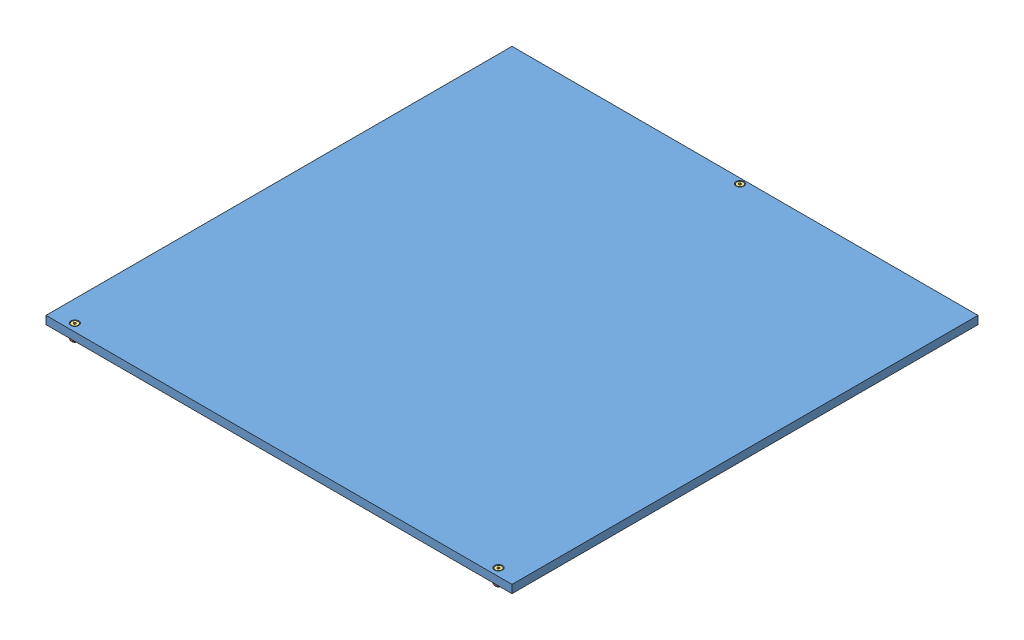
SolidWorks assembly Assem1, configuration Default. Lengths in mm.
Overall size (550 18.52 550.07).
7 component instances, 3 part files, 9 mates.
Components (placement in the parent):
- 550x550_plate-1: 550x550_plate [Default] at origin size (550 9.53 550)
- m4_threaded_ball_10mm-1: m4_threaded_ball_10mm [Default] at (-250 -9 266) x (0.969288 0 -0.24593) z (0.24593 0 0.969288) size (10 9 10)
- m4_threaded_ball_10mm-2: m4_threaded_ball_10mm [Default] at (0 -9 -268.9976) x (0.969288 0 -0.24593) z (0.24593 0 0.969288) size (10 9 10)
- m4_threaded_ball_10mm-3: m4_threaded_ball_10mm [Default] at (250 -9 266) x (0.969288 0 -0.24593) z (0.24593 0 0.969288) size (10 9 10)
- socket countersunk head screw_am-1: socket countersunk head screw_am [B18.3.5M - 4 x 0.7 x 12 Socket FCHS  -- 12N] at (-250 9.305 266) x (0 -1 0) z (0.00391 0 0.999992) size (12 7.8 7.8)
- socket countersunk head screw_am-2: socket countersunk head screw_am [B18.3.5M - 4 x 0.7 x 12 Socket FCHS  -- 12N] at (250 9.305 266) x (0 -1 0) z (-0.007018 0 0.999975) size (12 7.8 7.8)
- socket countersunk head screw_am-3: socket countersunk head screw_am [B18.3.5M - 4 x 0.7 x 12 Socket FCHS  -- 12N] at (0 9.305 -268.9976) x (0 -1 0) z (-0.010842 0 0.999941) size (12 7.8 7.8)
Mates (geometry in assembly coordinates):
- Concentric1: concentric aligned: cylinder of 550x550_plate-1 through (-250 9.525 266) axis (0 1 0) radius 2.25; cylinder of m4_threaded_ball_10mm-1 through (-250 0 266) axis (0 1 0) radius 1.65
- Coincident1: coincident anti-aligned: plane of 550x550_plate-1 through (0 0 0) normal (0 -1 0); plane of m4_threaded_ball_10mm-1 through (-250 0 266) normal (0 1 0)
- Coincident2: coincident aligned: cone of 550x550_plate-1 through (-250 9.525 266) axis (0 -1 0); cone of socket countersunk head screw_am-1 through (-250 8.725 266) axis (0 -1 0)
- Coincident3: coincident aligned: cone of 550x550_plate-1 through (250 9.525 266) axis (0 -1 0); cone of socket countersunk head screw_am-2 through (250 8.725 266) axis (0 -1 0)
- Coincident4: coincident aligned: cone of 550x550_plate-1 through (0 9.525 -268.9976) axis (0 -1 0); cone of socket countersunk head screw_am-3 through (0 8.725 -268.9976) axis (0 -1 0)
- Concentric2: concentric aligned: cylinder of socket countersunk head screw_am-2 through (250 9.305 266) axis (0 1 0) radius 2; cylinder of m4_threaded_ball_10mm-3 through (250 0 266) axis (0 1 0) radius 1.65
- Coincident5: coincident anti-aligned: plane of 550x550_plate-1 through (0 0 0) normal (0 -1 0); plane of m4_threaded_ball_10mm-3 through (250 0 266) normal (0 1 0)
- Coincident6: coincident anti-aligned: plane of 550x550_plate-1 through (0 0 0) normal (0 -1 0); plane of m4_threaded_ball_10mm-2 through (0 0 -268.9976) normal (0 1 0)
- Concentric3: concentric aligned: cylinder of socket countersunk head screw_am-3 through (0 9.305 -268.9976) axis (0 1 0) radius 2; cylinder of m4_threaded_ball_10mm-2 through (0 0 -268.9976) axis (0 1 0) radius 1.65
